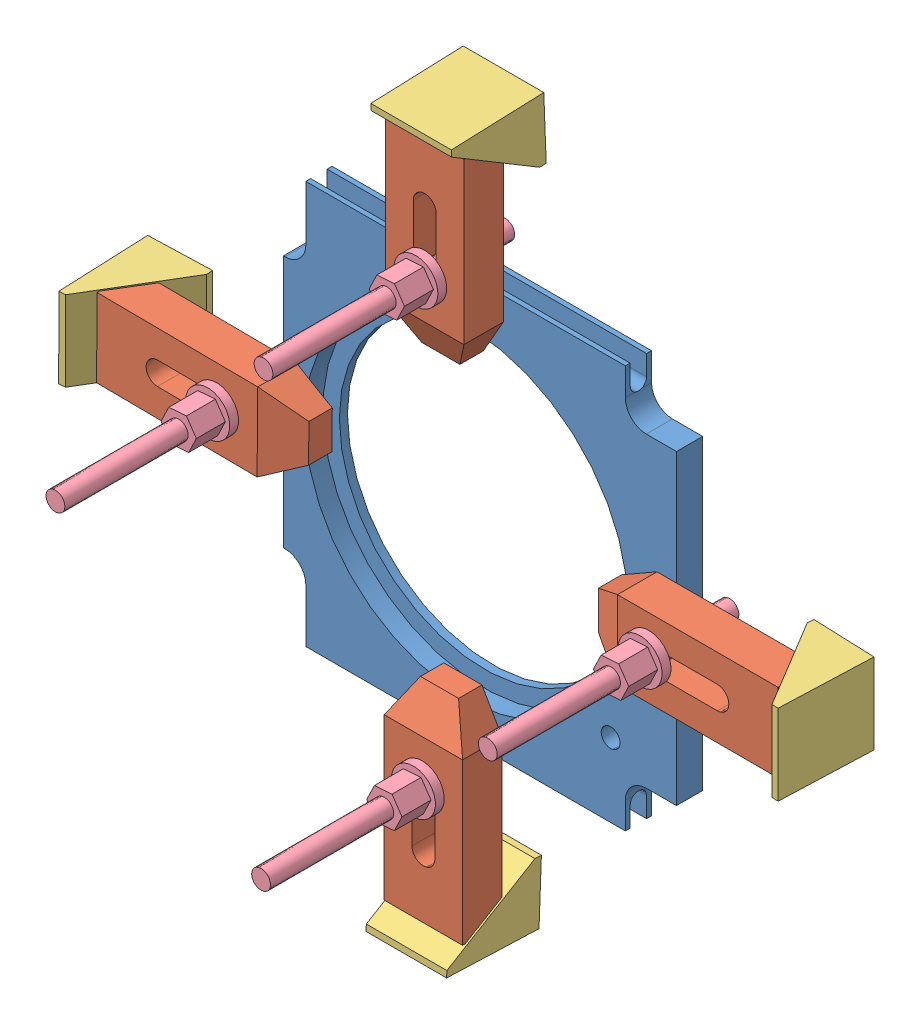
SolidWorks assembly Fixture-undercut-BobCAD-crash, configuration All clamps. Lengths in mm.
Overall size (229.08 227.81 79.09).
13 component instances, 4 part files, 8 mates.
Components (placement in the parent):
- Fixture-undercut-part-1: Fixture-undercut-part [Default] at (57.186 0 0) x (0 0 1) z (-1 0 0) size (8.26 127 123.95)
- Short-clamp-toe-2: Short-clamp-toe [Default] at (59.2079 6.7742 10.9361) x (0 1 0) z (0 0 1) size (61.72 24.71 12.45)
- Short-clamp-toe-4: Short-clamp-toe [Default] at (59.0701 0.941 11.2202) x (0 -1 0) z (0 0 1) size (61.72 24.71 12.45)
- Short-clamp-wedge-2: Short-clamp-wedge [Default] at (46.6068 2.3759 -4.1451) x (0 0.038151 0.999272) z (1 0 0) size (29.14 19.72 25.4)
- Short-clamp-wedge-3: Short-clamp-wedge [Default] at (72.2619 4.7581 -5.3977) x (0 -0.038151 0.999272) z (-1 0 0) size (29.14 19.72 25.4)
- Short-clamp-bolt-3: Short-clamp-bolt [Default] at (-10.9915 73.142 23.3821) size (13.89 13.89 76.2)
- Short-clamp-bolt-4: Short-clamp-bolt [Default] at (-11.4778 -66.3426 23.6662) size (13.89 13.89 76.2)
- Short-clamp-toe-1: Short-clamp-toe [Default] at (63.63 1.5156 8.3277) size (61.72 24.71 12.45)
- Short-clamp-toe-3: Short-clamp-toe [Default] at (57.6843 1.1605 8.431) x (-0.999962 0.008727 0) z (0 0 1) size (61.72 24.71 12.45)
- Short-clamp-wedge-1: Short-clamp-wedge [Default] at (62.4804 -11.1414 -6.5623) x (-0.038151 0 0.999272) z (0 1 0) size (29.14 19.72 25.4)
- Short-clamp-wedge-4: Short-clamp-wedge [Default] at (58.9859 14.2162 -6.5221) x (0.03812 -0.004212 0.999264) z (-0.006342 -0.999972 -0.003973) size (29.14 19.72 25.4)
- Short-clamp-bolt-1: Short-clamp-bolt [Default] at (-79.0962 1.7202 20.877) size (13.89 13.89 76.2)
- Short-clamp-bolt-2: Short-clamp-bolt [Default] at (57.0997 2.0951 20.7737) size (13.89 13.89 76.2)
Mates (geometry in assembly coordinates):
- Coincident3: coincident anti-aligned: plane of Short-clamp-toe-3 through (-46.7775 -10.2854 20.0702) normal (-0.857411 0.007483 -0.514578); plane of Short-clamp-wedge-4 through (-50.7738 -10.6204 26.724) normal (0.857411 -0.007483 0.514578)
- Coincident4: coincident anti-aligned: plane of Short-clamp-toe-4 through (71.4272 -103.417 22.8593) normal (0 -0.857444 -0.514578); plane of Short-clamp-wedge-2 through (72.0068 -107.2239 29.2027) normal (0 0.857444 0.514578)
- Coincident5: coincident anti-aligned: plane of Short-clamp-toe-1 through (167.988 13.8727 19.9668) normal (0.857444 0 -0.514578); plane of Short-clamp-wedge-1 through (172.0801 14.2586 26.7855) normal (-0.857444 0 0.514578)
- Coincident6: coincident anti-aligned: plane of Short-clamp-toe-2 through (46.8508 111.1321 22.5752) normal (0 0.857444 -0.514578); plane of Short-clamp-wedge-3 through (46.8619 114.3578 27.9502) normal (0 -0.857444 0.514578)
- Coincident7: coincident anti-aligned: plane of Short-clamp-toe-4 through (59.0701 0.941 23.6662) normal (0 0 1); plane of Short-clamp-bolt-4 through (58.6971 -66.3426 23.6662) normal (0 0 -1)
- Coincident8: coincident anti-aligned: plane of Short-clamp-toe-3 through (57.6843 1.1605 20.877) normal (0 0 1); plane of Short-clamp-bolt-1 through (-8.9214 1.7202 20.877) normal (0 0 -1)
- Coincident9: coincident anti-aligned: plane of Short-clamp-toe-2 through (59.2079 6.7742 23.3821) normal (0 0 1); plane of Short-clamp-bolt-3 through (59.1834 73.142 23.3821) normal (0 0 -1)
- Coincident10: coincident anti-aligned: plane of Short-clamp-toe-1 through (63.63 1.5156 20.7737) normal (0 0 1); plane of Short-clamp-bolt-2 through (127.2745 2.0951 20.7737) normal (0 0 -1)
